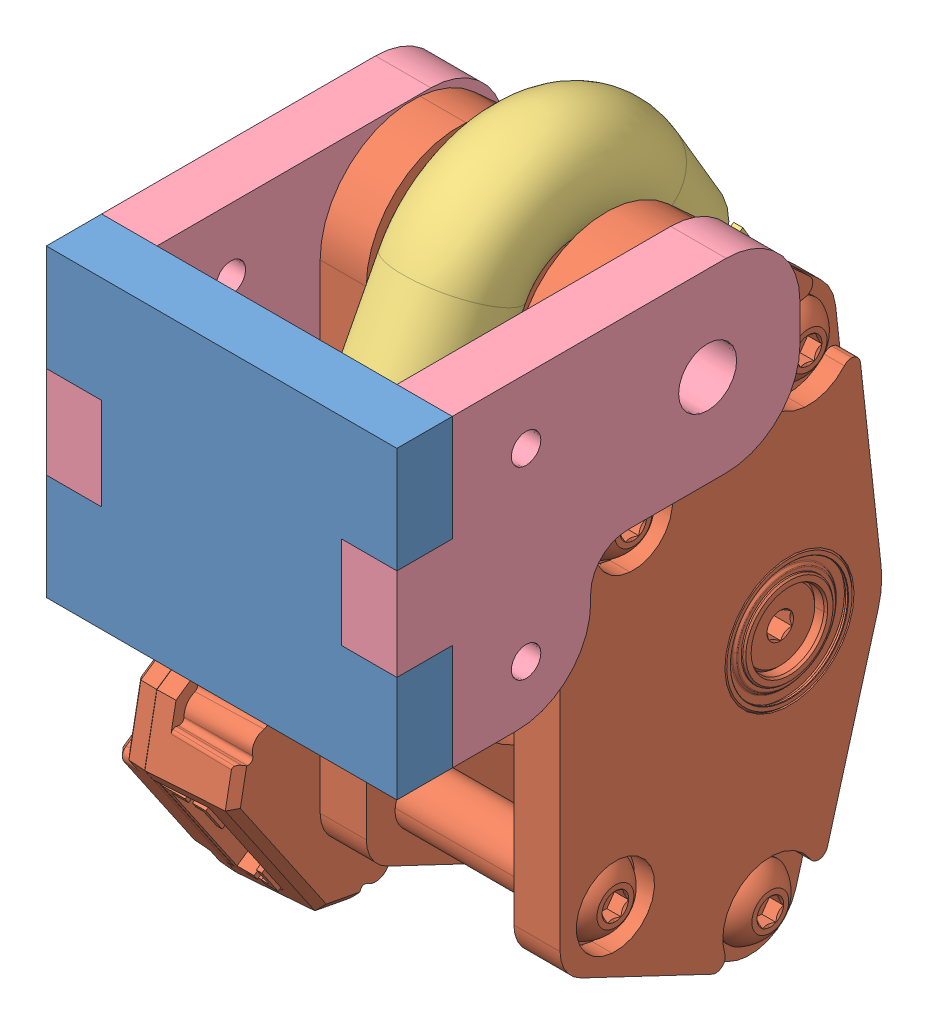
SolidWorks assembly Suporte odometria vertical, configuration Valor predeterminado. Lengths in mm.
Overall size (45.85 85.53 69.49).
5 component instances, 4 part files, 12 mates.
Components (placement in the parent):
- M04.03.06.Superior 6-1: M04.03.06.Superior 6 [Valor predeterminado] at (-50.2048 0.7174 124.5588) x (0 -1 0) z (0 0 1) size (33 38 6)
- M04.03.08.Odometria-2: M04.03.08.Odometria [Valor predeterminado] at (-56.543 -16.2561 82.8886) x (0 -0.996661 0.081653) z (1 0 0) size (73.49 51.17 39.86)
- M04.03.09.Mola-1: M04.03.09.Mola [Valor predeterminado] at (-50.2048 6.805 96.689) x (0 -0.980257 0.197728) z (-1 0 0) size (38.69 42.17 12)
- M04.03.05.Lateral vertical-1: M04.03.05.Lateral vertical [Valor predeterminado] at (-63.2048 26.2174 124.5588) x (0 -1 0) z (-1 0 0) size (33 43.68 6)
- M04.03.05.Lateral vertical-2: M04.03.05.Lateral vertical [Valor predeterminado] at (-31.2048 26.2174 124.5588) x (0 -1 0) z (-1 0 0) size (33 43.68 6)
Mates (geometry in assembly coordinates):
- Paralelo1: parallel: plane of M04.03.06.Superior 6-1 through (-50.2048 0.7174 130.5588) normal (0 0 1); line of M04.03.08.Odometria-2 through (-58.2048 7.0674 106.8779) axis (0 -1 0)
- Concêntrico18: concentric anti-aligned: cylinder of M04.03.08.Odometria-2 through (-42.2048 -1.8814 79.9395) axis (-1 0 0) radius 2.975; cylinder of M04.03.09.Mola-1 through (-45.2048 -1.8814 79.9395) axis (1 0 0) radius 4
- Coincidente1: coincident anti-aligned: plane of M04.03.06.Superior 6-1 through (-63.2048 0.7174 130.5588) normal (-1 0 0); plane of M04.03.05.Lateral vertical-1 through (-63.2048 26.2174 124.5588) normal (1 0 0)
- Coincidente2: coincident anti-aligned: plane of M04.03.06.Superior 6-1 through (-50.2048 0.7174 124.5588) normal (0 0 -1); plane of M04.03.05.Lateral vertical-1 through (-69.2048 26.2174 124.5588) normal (0 0 1)
- Coincidente3: coincident anti-aligned: plane of M04.03.06.Superior 6-1 through (-50.2048 5.7174 130.5588) normal (0 -1 0); plane of M04.03.05.Lateral vertical-1 through (-69.2048 5.7174 124.5588) normal (0 1 0)
- Concêntrico19: concentric anti-aligned: cylinder of M04.03.08.Odometria-2 through (-58.2048 7.0674 96.8779) axis (-1 0 0) radius 3; cylinder of M04.03.05.Lateral vertical-1 through (-69.2048 7.0674 96.8779) axis (1 0 0) radius 3.15
- Coincidente4: coincident anti-aligned: plane of M04.03.06.Superior 6-1 through (-37.2048 0.7174 130.5588) normal (1 0 0); plane of M04.03.05.Lateral vertical-2 through (-37.2048 26.2174 124.5588) normal (-1 0 0)
- Coincidente5: coincident anti-aligned: plane of M04.03.06.Superior 6-1 through (-50.2048 -4.2826 130.5588) normal (0 1 0); plane of M04.03.05.Lateral vertical-2 through (-37.2048 -4.2826 124.5588) normal (0 -1 0)
- Coincidente6: coincident aligned: plane of M04.03.06.Superior 6-1 through (-50.2048 0.7174 130.5588) normal (0 0 1); plane of M04.03.05.Lateral vertical-2 through (-37.2048 26.2174 130.5588) normal (0 0 1)
- Concêntrico20: concentric aligned: circle of M04.03.09.Mola-1; cylinder of M04.03.05.Lateral vertical-2 through (-37.2048 -9.7826 116.5588) axis (1 0 0) radius 1.6
- Distância1: distance = 7 mm anti-aligned: plane of M04.03.05.Lateral vertical-2 through (-37.2048 26.2174 124.5588) normal (-1 0 0); plane of M04.03.09.Mola-1 through (-44.2048 6.805 96.689) normal (1 0 0)
- Coincidente9: coincident anti-aligned: plane of M04.03.08.Odometria-2 through (-37.2048 -20.3088 90.285) normal (1 0 0); plane of M04.03.05.Lateral vertical-2 through (-37.2048 26.2174 124.5588) normal (-1 0 0)
